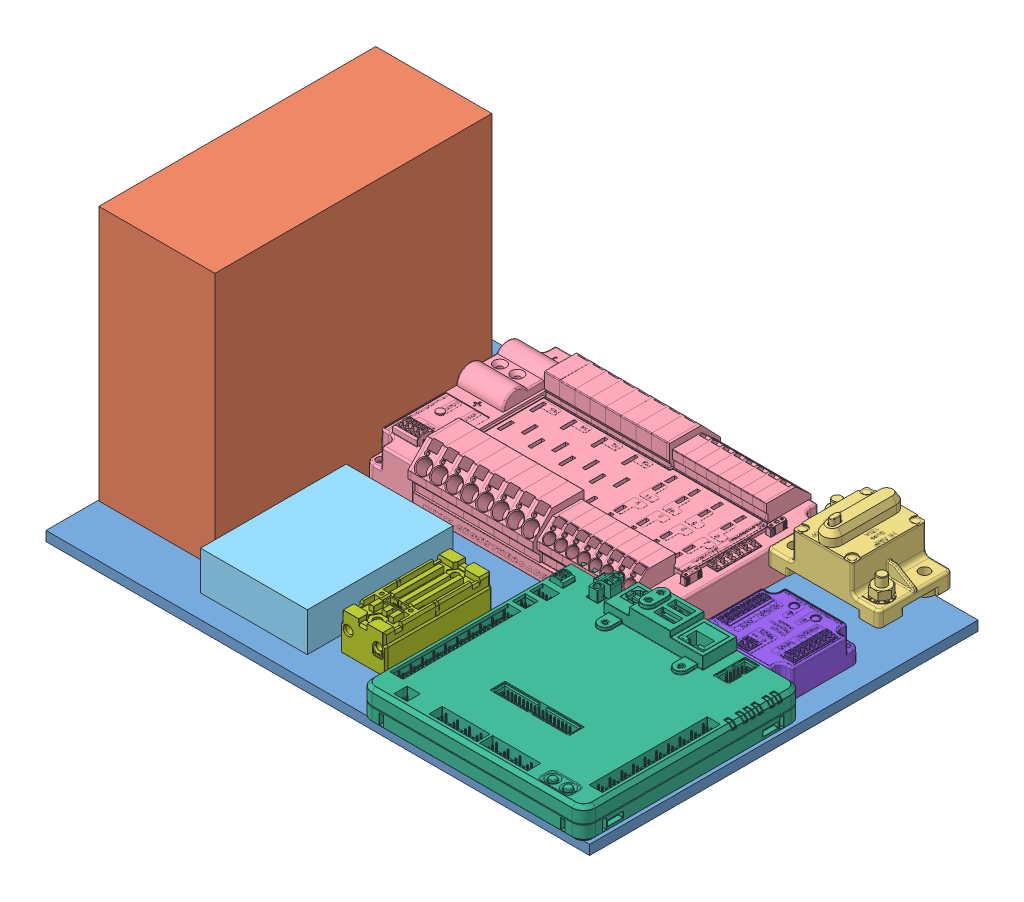
SolidWorks assembly Assem1, configuration Default. Lengths in mm.
Overall size (355.6 173.23 257.75).
8 component instances, 8 part files, 6 mates.
Components (placement in the parent):
- intial concept poly (14x10)-1: intial concept poly (14x10) [Default] at (-54.9491 160.7993 419.8425) size (355.6 6.35 254)
- Battery-1: Battery [Default] at (-54.3634 167.1493 385.8539) size (75.95 166.88 181.1)
- Breaker-1: Breaker [Default] at (257.9186 193.125 200.6469) size (73.72 42.2 48.95)
- PDP-1: PDP [Default] at (121.456 173.8295 229.8474) size (192.68 36.15 120.93)
- radio b;ock-1: radio b;ock [Default] at (31.0295 167.1493 404.7275) size (69.85 25.4 95.25)
- Roborio-1: Roborio [Default] at (227.4171 176.8013 351.9962) x (1 0 0) z (0 1 0) size (146.27 143.19 36.83)
- Speed Controller-1: Speed Controller [Default] at (124.5959 182.9868 357.1778) x (1 0 0) z (0 -1 0) size (30.12 70.11 24.39)
- VRM-1: VRM [Default] at (257.8169 174.2552 251.8326) size (56.39 19.92 51.56)
Mates (geometry in assembly coordinates):
- Coincident1: coincident anti-aligned: plane of intial concept poly (14x10)-1 through (-54.9491 167.1493 419.8425) normal (0 1 0); plane of radio b;ock-1 through (31.0295 167.1493 404.7275) normal (0 -1 0)
- Coincident2: coincident anti-aligned: plane of intial concept poly (14x10)-1 through (-54.9491 167.1493 419.8425) normal (0 1 0); plane of PDP-1 through (213.4802 167.1493 287.2514) normal (0 -1 0)
- Coincident3: coincident anti-aligned: plane of intial concept poly (14x10)-1 through (-54.9491 167.1493 419.8425) normal (0 1 0); plane of Battery-1 through (-54.3634 167.1493 385.8539) normal (0 -1 0)
- Coincident4: coincident aligned: plane of intial concept poly (14x10)-1 through (-54.9491 167.1493 419.8425) normal (0 1 0); plane of Roborio-1 through (153.9051 167.1493 423.9628) normal (0 1 0)
- Coincident5: coincident anti-aligned: plane of intial concept poly (14x10)-1 through (-54.9491 167.1493 419.8425) normal (0 1 0); plane of Speed Controller-1 through (139.6582 167.1493 322.2528) normal (0 -1 0)
- Coincident6: coincident anti-aligned: plane of intial concept poly (14x10)-1 through (-54.9491 167.1493 419.8425) normal (0 1 0); plane of VRM-1 through (281.1612 167.1493 232.2854) normal (0 -1 0)
